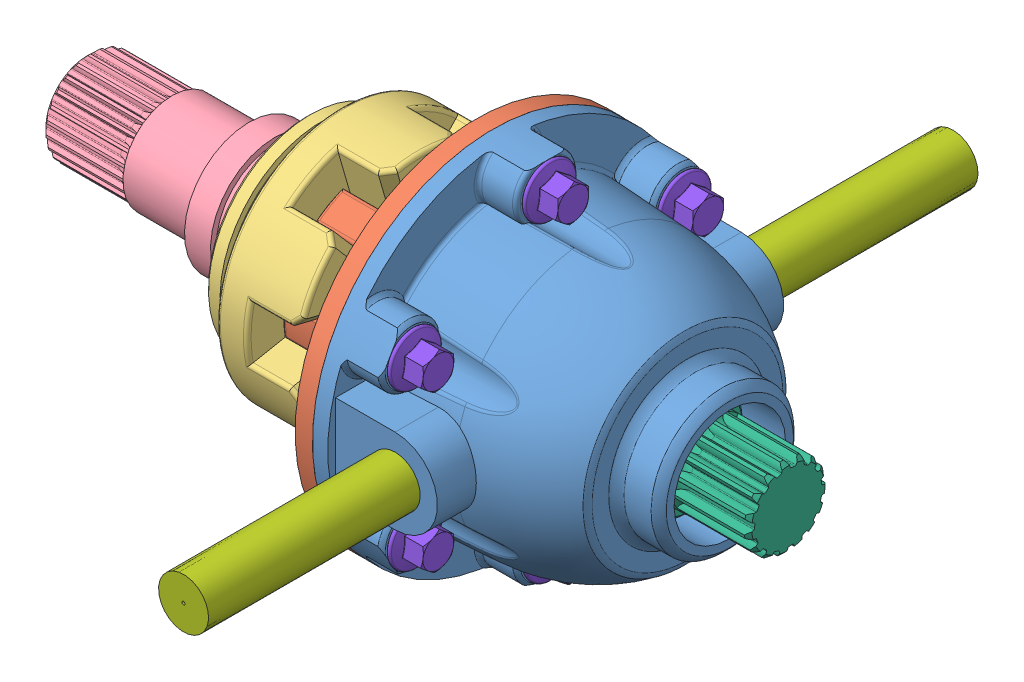
SolidWorks assembly car gear assembly, configuration Default. Lengths in mm.
Overall size (182.2 128.41 200).
14 component instances, 8 part files, 31 mates.
Components (placement in the parent):
- Part1-1: Part1 [Default] at (57.676 34.7732 55.1552) size (61.51 94.87 94)
- Second cover-1: Second cover [Default] at (61.176 34.7732 55.1552) x (1 0 0) z (0 0.866025 0.5) size (36 94 94)
- joint-1: joint [Default] at (26.176 34.7732 55.1552) x (0 -0.026177 -0.999657) z (0 0.999657 -0.026177) size (64.88 32.06 64.88)
- Shaft1-1: Shaft1 [Default] at (-47.824 34.7732 55.1552) x (1 0 0) z (0 0.98065 0.195771) size (116.5 33.5 33.5)
- Gear Part2-1: Gear Part2 [Default] at (73.2826 27.5648 57.2945) x (1 0 0) z (0 0.997904 -0.06471) size (10.63 40.95 40.95)
- gear 2.1-1: gear 2.1 [Default] at (55.3105 54.4542 54.9095) x (-1 0 0) z (0 -0.970037 0.242958) size (47.63 40.95 40.95)
- straight bevel gear_iso-1: straight bevel gear_iso [ISO - Straight bevel gear 1M 30GT 40PT 20PA 8FW ---30O13H100MD0.8N] at (77.176 34.7732 75.7786) x (0 0 -1) z (-0.996357 0.085275 0) size (87.36 32.09 32.25)
- straight bevel gear_iso-2: straight bevel gear_iso [ISO - Straight bevel gear 1M 30GT 40PT 20PA 8FW ---30O13H100MD0.8N] at (77.176 34.7732 34.5317) x (0 0 1) z (0.878233 0.478234 0) size (87.36 32.09 32.25)
- hex flange bolt small_bsi-1: hex flange bolt small_bsi [BS EN ISO 4162 - M6 x 20 x 20-N] at (78.476 55.0232 90.2292) x (-1 0 0) z (0 0.924225 0.381849) size (26.8 13.6 13.6)
- hex flange bolt small_bsi-2: hex flange bolt small_bsi [BS EN ISO 4162 - M6 x 20 x 20-N] at (78.476 75.2732 55.1552) x (-1 0 0) z (0 0.924225 0.381849) size (26.8 13.6 13.6)
- hex flange bolt small_bsi-4: hex flange bolt small_bsi [BS EN ISO 4162 - M6 x 20 x 20-N] at (78.476 55.0232 20.0811) x (-1 0 0) z (0 0.924225 0.381849) size (26.8 13.6 13.6)
- hex flange bolt small_bsi-5: hex flange bolt small_bsi [BS EN ISO 4162 - M6 x 20 x 20-N] at (78.476 14.5232 90.2292) x (-1 0 0) z (0 0.924225 0.381849) size (26.8 13.6 13.6)
- hex flange bolt small_bsi-6: hex flange bolt small_bsi [BS EN ISO 4162 - M6 x 20 x 20-N] at (78.476 -5.7268 55.1552) x (-1 0 0) z (0 0.924225 0.381849) size (26.8 13.6 13.6)
- hex flange bolt small_bsi-7: hex flange bolt small_bsi [BS EN ISO 4162 - M6 x 20 x 20-N] at (78.476 14.5232 20.0811) x (-1 0 0) z (0 0.924225 0.381849) size (26.8 13.6 13.6)
Mates (geometry in assembly coordinates):
- Concentric1: concentric aligned: cylinder of Part1-1 through (57.676 34.7732 55.1552) axis (1 0 0) radius 14.5; cylinder of Second cover-1 through (61.176 34.7732 55.1552) axis (1 0 0) radius 12.5
- Concentric2: concentric anti-aligned: cylinder of Second cover-1 through (61.176 34.7732 55.1552) axis (1 0 0) radius 12.5; cylinder of joint-1 through (11.7377 34.7732 55.1552) axis (-1 0 0) radius 15.25
- Coincident1: coincident anti-aligned: plane of Second cover-1 through (39.176 50.7759 49.6012) normal (0 0.327878 0.94472); plane of joint-1 through (39.176 50.8335 49.5812) normal (0 -0.327878 -0.94472)
- Coincident2: coincident anti-aligned: plane of Second cover-1 through (39.176 35.8095 55.1552) normal (-1 0 0); plane of joint-1 through (39.176 34.7732 55.1552) normal (1 0 0)
- Concentric3: concentric anti-aligned: cylinder of Second cover-1 through (61.176 34.7732 55.1552) axis (1 0 0) radius 12.5; cylinder of Shaft1-1 through (-47.824 34.7732 55.1552) axis (-1 0 0) radius 15.25
- Coincident4: coincident anti-aligned: plane of Shaft1-1 through (66.176 36.633 45.839) normal (-1 0 0); plane of Gear Part2-1 through (66.176 34.7732 55.1552) normal (1 0 0)
- Concentric5: concentric anti-aligned: cylinder of Shaft1-1 through (-47.824 34.7732 55.1552) axis (-1 0 0) radius 15.25; cylinder of Gear Part2-1 through (57.3213 34.7732 55.1552) axis (1 0 0) radius 14
- Concentric6: concentric aligned: cylinder of Shaft1-1 through (47.176 24.0743 54.1082) axis (1 0 0) radius 3.2; cylinder of Gear Part2-1 through (49.176 24.0743 54.1082) axis (1 0 0) radius 3.2
- Concentric8: concentric anti-aligned: cylinder of Part1-1 through (57.676 34.7732 55.1552) axis (1 0 0) radius 14.5; cylinder of gear 2.1-1 through (97.3715 34.7732 55.1552) axis (-1 0 0) radius 14
- Concentric10: concentric aligned: cylinder of Part1-1 through (77.176 34.7732 500055.1552) axis (0 0 -1) radius 6.5; cylinder of straight bevel gear_iso-1 through (77.176 34.7732 155.1553) axis (0 0 -1) radius 6.5
- Coincident5: coincident: line of Part1-1 through (62.6237 34.7732 55.1552) axis (1 0 0); point of straight bevel gear_iso-1
- GearMate1: gear = 30 : 40 mm: circle of gear 2.1-1; circle of straight bevel gear_iso-1
- Concentric12: concentric aligned: cylinder of Part1-1 through (77.176 34.7732 8.1552) axis (0 0 1) radius 6.5; cylinder of straight bevel gear_iso-2 through (77.176 34.7732 -44.8449) axis (0 0 1) radius 6.5
- Coincident6: coincident: line of Part1-1 through (62.6237 34.7732 55.1552) axis (1 0 0); unknown of straight bevel gear_iso-2
- GearMate2: gear = 30 : 40 mm: circle of gear 2.1-1; circle of straight bevel gear_iso-2
- Distance1: distance = 11 mm: line of straight bevel gear_iso-2 through (77.176 34.7732 24.5317) axis (0 0 1); plane of Gear Part2-1 through (66.176 34.7732 55.1552) normal (1 0 0)
- GearMate3: gear = 30 : 40 mm: circle of Gear Part2-1; circle of straight bevel gear_iso-1
- Coincident8: coincident anti-aligned: plane of Part1-1 through (57.676 81.7732 55.1552) normal (-1 0 0); plane of Second cover-1 through (57.676 17.7732 84.6) normal (1 0 0)
- Concentric14: concentric anti-aligned: cylinder of Part1-1 through (57.676 14.5232 20.0811) axis (1 0 0) radius 3; cylinder of Second cover-1 through (61.176 14.5232 20.0811) axis (-1 0 0) radius 3
- Concentric15: concentric aligned: cylinder of Part1-1 through (57.676 55.0232 90.2292) axis (1 0 0) radius 3; cylinder of hex flange bolt small_bsi-1 through (78.476 55.0232 90.2292) axis (1 0 0) radius 3
- Coincident9: coincident anti-aligned: plane of Part1-1 through (71.676 34.7732 55.1552) normal (1 0 0); plane of hex flange bolt small_bsi-1 through (71.676 53.2595 94.498) normal (-1 0 0)
- Concentric16: concentric aligned: cylinder of Part1-1 through (57.676 75.2732 55.1552) axis (1 0 0) radius 3; cylinder of hex flange bolt small_bsi-2 through (78.476 75.2732 55.1552) axis (1 0 0) radius 3
- Coincident10: coincident anti-aligned: plane of Part1-1 through (71.676 34.7732 55.1552) normal (1 0 0); plane of hex flange bolt small_bsi-2 through (71.676 73.5095 59.424) normal (-1 0 0)
- Concentric18: concentric aligned: cylinder of Part1-1 through (57.676 55.0232 20.0811) axis (1 0 0) radius 3; cylinder of hex flange bolt small_bsi-4 through (78.476 55.0232 20.0811) axis (1 0 0) radius 3
- Coincident11: coincident anti-aligned: plane of Part1-1 through (71.676 34.7732 55.1552) normal (1 0 0); plane of hex flange bolt small_bsi-4 through (71.676 53.2595 24.3499) normal (-1 0 0)
- Concentric19: concentric aligned: cylinder of Part1-1 through (57.676 14.5232 90.2292) axis (1 0 0) radius 3; cylinder of hex flange bolt small_bsi-5 through (78.476 14.5232 90.2292) axis (1 0 0) radius 3
- Coincident12: coincident anti-aligned: plane of Part1-1 through (71.676 34.7732 55.1552) normal (1 0 0); plane of hex flange bolt small_bsi-5 through (71.676 12.7595 94.498) normal (-1 0 0)
- Concentric20: concentric aligned: cylinder of Part1-1 through (57.676 -5.7268 55.1552) axis (1 0 0) radius 3; cylinder of hex flange bolt small_bsi-6 through (78.476 -5.7268 55.1552) axis (1 0 0) radius 3
- Coincident13: coincident anti-aligned: plane of Part1-1 through (71.676 34.7732 55.1552) normal (1 0 0); plane of hex flange bolt small_bsi-6 through (71.676 -7.4905 59.424) normal (-1 0 0)
- Concentric21: concentric aligned: cylinder of Part1-1 through (57.676 14.5232 20.0811) axis (1 0 0) radius 3; cylinder of hex flange bolt small_bsi-7 through (78.476 14.5232 20.0811) axis (1 0 0) radius 3
- Coincident14: coincident anti-aligned: plane of Part1-1 through (71.676 34.7732 55.1552) normal (1 0 0); plane of hex flange bolt small_bsi-7 through (71.676 12.7595 24.3499) normal (-1 0 0)
